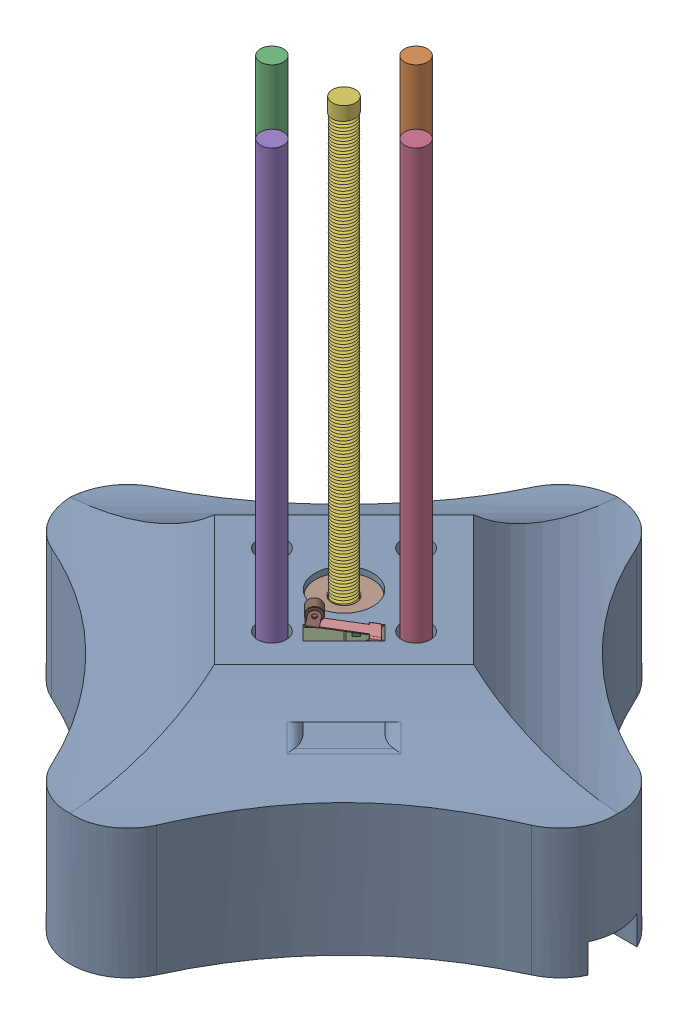
SolidWorks assembly Base - Ensamblaje, configuration Predeterminado. Lengths in mm.
Overall size (190 213 190).
12 component instances, 8 part files, 20 mates.
Components (placement in the parent):
- Base - B-1: Base - B [Predeterminado] at (-21.2506 -48.1849 95) size (190 65 190)
- Varilla - VE-1: Varilla - VE [Predeterminado] at (-21.2506 -3.1849 70) x (0.38047 0 -0.924793) z (0.924793 0 0.38047) size (8 168 8)
- Varilla - VE-2: Varilla - VE [Predeterminado] at (-46.2506 -3.1849 95) x (-0.904245 0 0.427014) z (-0.427014 0 -0.904245) size (8 168 8)
- Varilla - VE-3: Varilla - VE [Predeterminado] at (3.7494 -3.1849 95) x (0.407711 0 0.913111) z (-0.913111 0 0.407711) size (8 168 8)
- Varilla - VE-4: Varilla - VE [Predeterminado] at (-21.2506 -3.1849 120) x (0.918808 0 0.394705) z (-0.394705 0 0.918808) size (8 168 8)
- [THSL-300-8D-1MM-1H] Varilla trapezoidal roscada - VTR-1: [THSL-300-8D-1MM-1H] Varilla trapezoidal roscada - VTR [Predeterminado] at (-21.4906 9.8151 94.76) x (0.963795 0 0.266644) z (-0.266644 0 0.963795) size (9.24 156.4 8.21)
- Nema 17 - 17HS3401 Usongshine-1: Nema 17 - 17HS3401 Usongshine [Varsayılan] at (-21.4906 -48.1849 94.76) x (0 0 1) z (-1 0 0) size (42.02 55.03 47.51)
- Acople NEMA17 - A1-1: Acople NEMA17 - A1 [Default] at (-21.4906 -11.1849 94.76) x (0.759787 0 -0.650172) z (0.650172 0 0.759787) size (20 26 20)
- Fin de carrera-1: Fin de carrera [Default] at (-25.9222 -2.093 96.5264) x (0.707107 0 -0.707107) z (0.707107 0 0.707107) size (20.3 23.07 6.6)
  - Limit switch-1: Limit switch [Default] at (-5.6175 18.1081 17.0438) size (20 15.2 6.6)
  - steel-1: steel [Default] at (13.5838 19.3646 18.3438) x (-0.985639 0.168868 0) z (0 0 1) size (19 9.3 6.6)
  - roller-1: roller [Default] at (-2.8697 25.4809 18.3438) x (0 0 1) z (-1 0 0) size (4 5 5)
Mates (geometry in assembly coordinates):
- Concéntrica1: concentric aligned: cylinder of base-1 through (-46.2506 16.8151 95) axis (0 -1 0) radius 5; cylinder of Varilla - VE-2 through (-46.2506 164.8151 95) axis (0 -1 0) radius 4
- Concéntrica2: concentric anti-aligned: circle of base-1; cylinder of Varilla - VE-1 through (-21.2506 164.8151 70) axis (0 -1 0) radius 4
- Concéntrica3: concentric aligned: cylinder of base-1 through (-21.2506 16.8151 120) axis (0 -1 0) radius 5; cylinder of Varilla - VE-4 through (-21.2506 164.8151 120) axis (0 -1 0) radius 4
- Concéntrica4: concentric aligned: cylinder of base-1 through (3.7494 16.8151 95) axis (0 -1 0) radius 5; cylinder of Varilla - VE-3 through (3.7494 164.8151 95) axis (0 -1 0) radius 4
- Coincidente1: coincident anti-aligned: plane of base-1 through (-21.2506 -3.1849 95) normal (0 1 0); plane of Varilla - VE-4 through (-21.2506 -3.1849 120) normal (0 -1 0)
- Coincidente2: coincident anti-aligned: plane of base-1 through (-21.2506 -3.1849 95) normal (0 1 0); plane of Varilla - VE-3 through (3.7494 -3.1849 95) normal (0 -1 0)
- Coincidente3: coincident anti-aligned: plane of base-1 through (-21.2506 -3.1849 95) normal (0 1 0); plane of Varilla - VE-1 through (-21.2506 -3.1849 70) normal (0 -1 0)
- Coincidente4: coincident anti-aligned: plane of base-1 through (-21.2506 -3.1849 95) normal (0 1 0); plane of Varilla - VE-2 through (-46.2506 -3.1849 95) normal (0 -1 0)
- Coincidente5: coincident anti-aligned: plane of base-1 through (-42.5006 -4.1849 73.75) normal (0 0 1); plane of Step - Nema 17 - 17HS3401 - Usongshine-1 through (-21.4906 -48.1849 73.75) normal (0 0 -1)
- Coincidente6: coincident anti-aligned: plane of base-1 through (-42.5006 -4.1849 116.25) normal (1 0 0); plane of Step - Nema 17 - 17HS3401 - Usongshine-1 through (-42.5006 -48.1849 94.76) normal (-1 0 0)
- Coincidente8: coincident aligned: plane of base-1 through (-21.2506 -48.1849 95) normal (0 -1 0); plane of Step - Nema 17 - 17HS3401 - Usongshine-1 through (-21.4906 -48.1849 94.76) normal (0 -1 0)
- Concéntrica5: concentric aligned: circle of Step - Nema 17 - 17HS3401 - Usongshine-1; cylinder of NEMA17_Coupler-1 through (-21.4906 -11.1849 94.76) axis (0 -1 0) radius 2.52
- Distancia1: distance = 2 mm anti-aligned: plane of Step - Nema 17 - 17HS3401 - Usongshine-1 through (-21.4906 -13.1849 94.76) normal (0 1 0); plane of NEMA17_Coupler-1 through (-19.386 -11.1849 92.959) normal (0 -1 0)
- Concéntrica6: concentric aligned: cylinder of [THSL-300-8D-1MM-1H] Varilla trapezoidal roscada - VTR-1 through (-21.4906 164.8151 94.76) axis (0 -1 0) radius 4; cylinder of NEMA17_Coupler-1 through (-21.4906 -11.1849 94.76) axis (0 -1 0) radius 4.025
- Paralelo1: parallel aligned: plane of base-1 through (-21.2506 16.8151 95) normal (0 1 0); plane of NEMA17_Coupler-1 through (-14.0826 14.8151 88.4208) normal (0 1 0)
- Paralelo2: parallel aligned: plane of Varilla - VE-2 through (-46.2506 164.8151 95) normal (0 1 0); plane of [THSL-300-8D-1MM-1H] Varilla trapezoidal roscada - VTR-1 through (-21.4906 164.8151 94.76) normal (0 1 0)
- Coincidente14: coincident aligned: plane of Varilla - VE-2 through (-46.2506 164.8151 95) normal (0 1 0); plane of [THSL-300-8D-1MM-1H] Varilla trapezoidal roscada - VTR-1 through (-21.4906 164.8151 94.76) normal (0 1 0)
- Coincidente15: coincident anti-aligned: plane of base-1 through (-12.8928 2.8151 117.5001) normal (0.707107 0 -0.707107); plane of Assem1-1/Limit switch-1 through (-13.1757 16.0151 117.2173) normal (-0.707107 0 0.707107)
- Coincidente16: coincident anti-aligned: plane of base-1 through (-17.8426 2.8151 112.5504) normal (0.707107 0 0.707107); plane of Assem1-1/Limit switch-1 through (-17.8426 16.0151 112.5504) normal (-0.707107 0 -0.707107)
- Coincidente17: coincident anti-aligned: plane of base-1 through (-21.2506 2.8151 95) normal (0 1 0); plane of Assem1-1/Limit switch-1 through (-17.8426 2.8151 112.5504) normal (0 -1 0)
